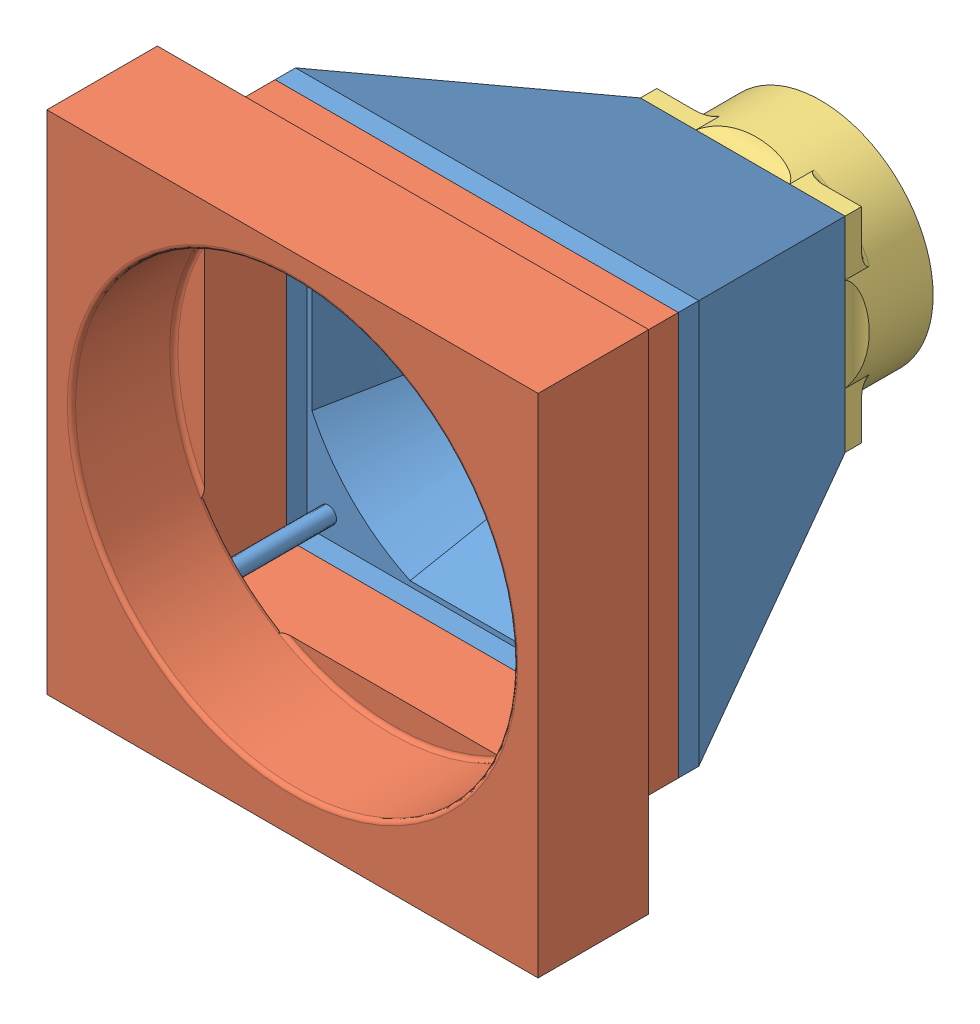
SolidWorks assembly Baugruppe1, configuration Standard. Lengths in mm.
Overall size (172.27 123.67 169.5).
3 component instances, 3 part files, 7 mates.
Components (placement in the parent):
- Lüfteradapter-1: Lüfteradapter [Standard] at (-40.1373 18.0929 25.0021) size (172.27 98.5 169.5)
- Lüfteradapter2-1: Lüfteradapter2 [Standard] at (-40.1373 18.0929 50.0021) x (-1 0 0) z (0 0 -1) size (120 123.67 45)
- Lüfteradapter_4-1: Lüfteradapter_4 [Standard] at (-40.1457 18.1013 -34.9979) x (-1 0 0) z (0 0 -1) size (55 55 20.56)
Mates (geometry in assembly coordinates):
- Parallel1: parallel aligned: plane of Lüfteradapter-1 through (-40.1373 -31.1571 30.0021) normal (0 -1 0); plane of Lüfteradapter2-1 through (-100.1373 -45.5756 75.0021) normal (0 -1 0)
- Deckungsgleich4: coincident aligned: plane of Lüfteradapter-1 through (-40.1373 -31.1571 30.0021) normal (0 -1 0); plane of Lüfteradapter2-1 through (-40.1373 -31.1571 30.0021) normal (0 -1 0)
- Deckungsgleich5: coincident aligned: plane of Lüfteradapter-1 through (-89.3873 18.0929 30.0021) normal (-1 0 0); plane of Lüfteradapter2-1 through (-89.3873 18.0929 30.0021) normal (-1 0 0)
- Deckungsgleich6: coincident anti-aligned: plane of Lüfteradapter-1 through (-40.1373 18.0929 30.0021) normal (0 0 1); plane of Lüfteradapter2-1 through (-40.1373 18.0929 30.0021) normal (0 0 -1)
- Deckungsgleich11: coincident anti-aligned: plane of Lüfteradapter-1 through (-40.1373 18.0929 -34.9979) normal (0 0 -1); plane of Lüfteradapter_4-1 through (-40.1457 18.1013 -34.9979) normal (0 0 1)
- Deckungsgleich12: coincident: point of Lüfteradapter-1; point of Lüfteradapter_4-1
- Parallel2: parallel aligned: line of Lüfteradapter_4-1 through (-15.1457 43.1013 -34.9979) axis (0 -1 0); line of Lüfteradapter-1 through (-15.1288 43.1013 -34.9979) axis (0 -1 0)
